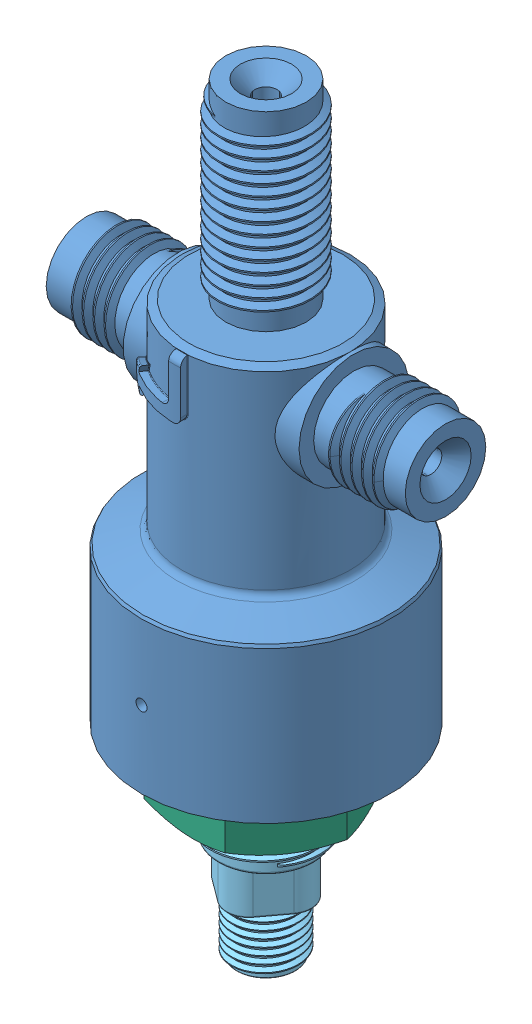
SolidWorks assembly СБОРКА, configuration По умолчанию. Lengths in mm.
Overall size (49 103.56 40.7).
6 component instances, 6 part files, 8 mates.
Components (placement in the parent):
- ГИГАШТУКА_СТРЕЛКА-1: ГИГАШТУКА_СТРЕЛКА [По умолчанию<Как обработанный>] at (-13.0964 -27.2417 -2.5064) size (49 76.92 39.01)
- МИНИШТУКА_ТИМУР-1: МИНИШТУКА_ТИМУР [По умолчанию] at (-13.0964 8.7583 -2.5064) x (0.971341 0 -0.237691) z (0.237691 0 0.971341) size (18 8 18)
- Пружина (2)-1: Пружина (2) [По умолчанию] at (-13.0964 -14.2417 -2.5064) size (18.03 21.49 18.03)
- Болт (2)-1: Болт (2) [По умолчанию] at (-13.0964 -15.7417 -2.5064) x (0.96556 0 -0.260181) z (0.260181 0 0.96556) size (18 23.5 18)
- вставштука_ТИМУР-1: вставштука_ТИМУР [По умолчанию] at (-13.0964 -54.7287 -2.5064) x (0.80264 0 0.596463) z (-0.596463 0 0.80264) size (19 38.58 19)
- Гайка (3)-1: Гайка (3) [По умолчанию] at (-13.0964 -11.6302 -2.5064) x (0.562546 0 -0.826766) z (0 -1 0) size (26.9 26.9 23.99)
Mates (geometry in assembly coordinates):
- Совпадение1: coincident anti-aligned: plane of ГИГАШТУКА_СТРЕЛКА-1 through (-13.0964 8.7583 -2.5064) normal (0 -1 0); plane of МИНИШТУКА_ТИМУР-1 through (-8.2397 8.7583 -3.6949) normal (0 1 0)
- Концентричный1: concentric aligned: cylinder of ГИГАШТУКА_СТРЕЛКА-1 through (-13.0964 8.7583 -2.5064) axis (0 -1 0) radius 9; cylinder of МИНИШТУКА_ТИМУР-1 through (-13.0964 8.7583 -2.5064) axis (0 -1 0) radius 5
- Совпадение2: coincident: point of Пружина (2)-1
- Совпадение3: coincident anti-aligned: plane of Пружина (2)-1 through (-13.0964 -14.2417 -2.5064) normal (0 -1 0); plane of Болт (2)-1 through (-17.4414 -14.2417 -1.3356) normal (0 1 0)
- Концентричный2: concentric aligned: cylinder of ГИГАШТУКА_СТРЕЛКА-1 through (-13.0964 8.7583 -2.5064) axis (0 -1 0) radius 9; cylinder of Болт (2)-1 through (-13.0964 -15.7417 -2.5064) axis (0 -1 0) radius 4.5
- Совпадение4: coincident anti-aligned: plane of МИНИШТУКА_ТИМУР-1 through (-4.3543 5.7583 -4.6456) normal (0 -1 0); plane of Пружина (2)-1 through (-13.0964 5.7583 -2.5064) normal (0 1 0)
- Концентричный3: concentric anti-aligned: cylinder of ГИГАШТУКА_СТРЕЛКА-1 through (-13.0964 8.7583 -2.5064) axis (0 -1 0) radius 9; cylinder of Гайка (3)-1 through (-13.0964 -27.6302 -2.5064) axis (0 1 0) radius 10
- Концентричный4: concentric aligned: cylinder of вставштука_ТИМУР-1 through (-13.0964 -18.7287 -2.5064) axis (0 1 0) radius 9.5; cylinder of Гайка (3)-1 through (-13.0964 -27.6302 -2.5064) axis (0 1 0) radius 10
